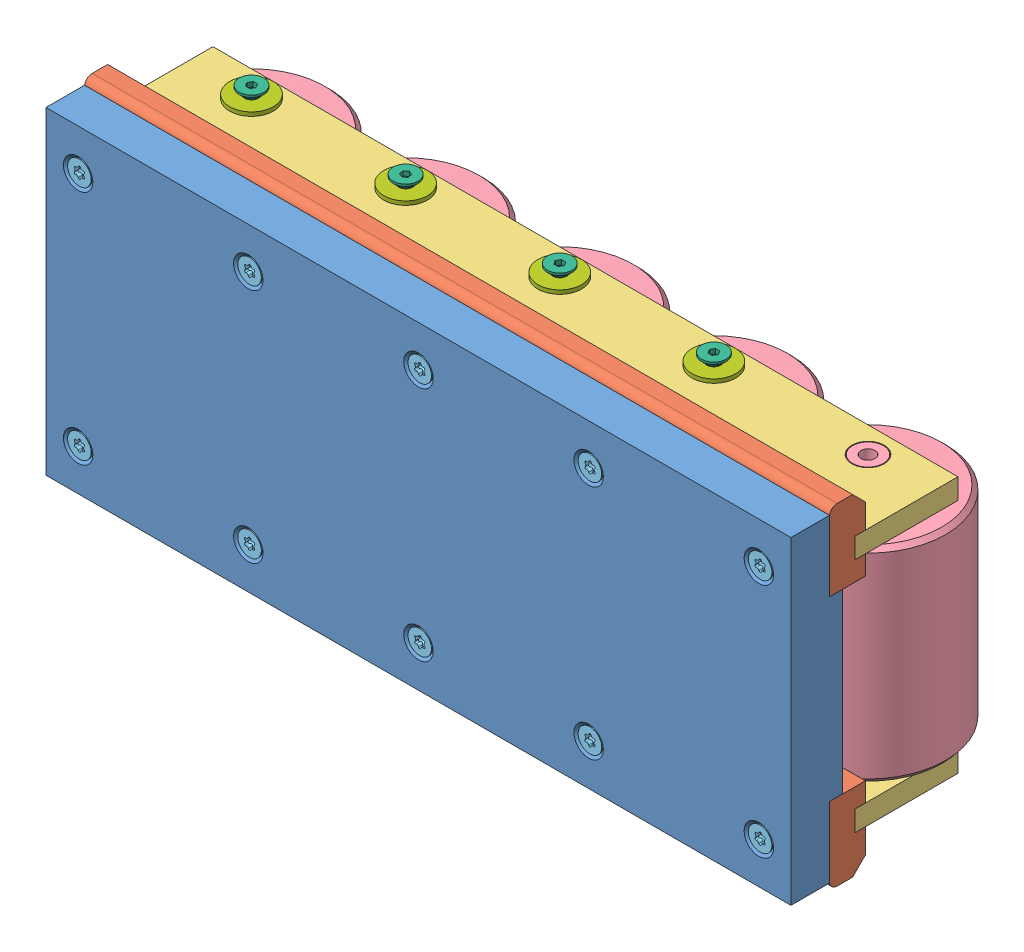
SolidWorks assembly Estrada Guerra Jorge Luis P60, configuration Predeterminado. Lengths in mm.
Overall size (604.52 258 194.9).
30 component instances, 7 part files, 54 mates.
Components (placement in the parent):
- P60.3-1: P60.3 [Predeterminado] at origin size (580 248 40)
- P60.2-1: P60.2 [Predeterminado] at (0 193 -58) x (1 0 0) z (0 -1 0) size (580 28 60)
- P60.2-2: P60.2 [Predeterminado] at (580 55 -58) x (-1 0 0) z (0 1 0) size (580 28 60)
- P60.1-2: P60.1 [Predeterminado] at (580 208 -130) x (0 1 0) z (1 0 0) size (16 80 580)
- P60.1-3: P60.1 [Predeterminado] at (0 40 -130) x (0 -1 0) z (-1 0 0) size (16 80 580)
- P60.4-1: P60.4 [Predeterminado] at (170 24 -110) x (-0.793535 0 0.608525) z (0 -1 0) size (121.11 121.11 200)
- P60.4-2: P60.4 [Predeterminado] at (290 24 -110) x (0.978566 0 -0.205935) z (0 -1 0) size (121.11 121.11 200)
- P60.4-3: P60.4 [Predeterminado] at (530 24 -110) x (1 0 0) z (0 -1 0) size (121.11 121.11 200)
- P60.4-4: P60.4 [Predeterminado] at (410 24 -110) x (1 0 0) z (0 -1 0) size (121.11 121.11 200)
- P60.4-5: P60.4 [Predeterminado] at (50 24 -110) x (0.998323 0 0.057885) z (0 -1 0) size (121.11 121.11 200)
- hexa csunk flathd screw_iso-1: hexa csunk flathd screw_iso [ISO 14581 M10x20x20-N] at (555 32 -1) size (18.3 18.3 20)
- hexa csunk flathd screw_iso-2: hexa csunk flathd screw_iso [ISO 14581 M10x20x20-N] at (555 216 -1) size (18.3 18.3 20)
- hexa csunk flathd screw_iso-3: hexa csunk flathd screw_iso [ISO 14581 M10x20x20-N] at (422.5 216 -1) size (18.3 18.3 20)
- hexa csunk flathd screw_iso-4: hexa csunk flathd screw_iso [ISO 14581 M10x20x20-N] at (157.5 32 -1) size (18.3 18.3 20)
- hexa csunk flathd screw_iso-5: hexa csunk flathd screw_iso [ISO 14581 M10x20x20-N] at (422.5 32 -1) size (18.3 18.3 20)
- hexa csunk flathd screw_iso-6: hexa csunk flathd screw_iso [ISO 14581 M10x20x20-N] at (290 32 -1) size (18.3 18.3 20)
- hexa csunk flathd screw_iso-7: hexa csunk flathd screw_iso [ISO 14581 M10x20x20-N] at (290 216 -1) size (18.3 18.3 20)
- hexa csunk flathd screw_iso-8: hexa csunk flathd screw_iso [ISO 14581 M10x20x20-N] at (157.5 216 -1) size (18.3 18.3 20)
- hexa csunk flathd screw_iso-9: hexa csunk flathd screw_iso [ISO 14581 M10x20x20-N] at (25 216 -1) size (18.3 18.3 20)
- hexa csunk flathd screw_iso-10: hexa csunk flathd screw_iso [ISO 14581 M10x20x20-N] at (25 32 -1) size (18.3 18.3 20)
- socket countersunk head screw_iso-1: socket countersunk head screw_iso [ISO 10642 - M10 x 50 - 50N] at (410 233.0828 -110) x (0 -1 0) z (0 0 1) size (50 19.22 19.22)
- plain washer xlarge grade c_iso-1: plain washer xlarge grade c_iso [Washer ISO 7094 - 10] at (410 224 -110) x (0 -1 0) z (0.546944 0 -0.837169) size (3 34 34)
- plain washer xlarge grade c_iso-2: plain washer xlarge grade c_iso [Washer ISO 7094 - 10] at (50 224 -110) x (0 -1 0) z (0.546944 0 -0.837169) size (3 34 34)
- socket countersunk head screw_iso-2: socket countersunk head screw_iso [ISO 10642 - M10 x 50 - 50N] at (50 233.0828 -110) x (0 -1 0) z (0 0 1) size (50 19.22 19.22)
- plain washer xlarge grade c_iso-3: plain washer xlarge grade c_iso [Washer ISO 7094 - 10] at (530 24 -110) x (0 1 0) z (0.546944 0 -0.837169) size (3 34 34)
- socket countersunk head screw_iso-3: socket countersunk head screw_iso [ISO 10642 - M10 x 50 - 50N] at (530 14.9172 -110) x (0 1 0) z (0 0 1) size (50 19.22 19.22)
- plain washer xlarge grade c_iso-4: plain washer xlarge grade c_iso [Washer ISO 7094 - 10] at (290 224 -110) x (0 -1 0) z (0.546944 0 -0.837169) size (3 34 34)
- socket countersunk head screw_iso-4: socket countersunk head screw_iso [ISO 10642 - M10 x 50 - 50N] at (290 233.0828 -110) x (0 -1 0) z (0 0 1) size (50 19.22 19.22)
- plain washer xlarge grade c_iso-5: plain washer xlarge grade c_iso [Washer ISO 7094 - 10] at (170 224 -110) x (0 -1 0) z (0.546944 0 -0.837169) size (3 34 34)
- socket countersunk head screw_iso-5: socket countersunk head screw_iso [ISO 10642 - M10 x 50 - 50N] at (170 233.0828 -110) x (0 -1 0) z (-0.346647 0 0.937996) size (50 19.22 19.22)
Mates (geometry in assembly coordinates):
- Coincidente1: coordinate: point of P60.3-1
- Coincidente2: coincident anti-aligned: plane of P60.3-1 through (580 248 -30) normal (0 0 -1); plane of P60.2-1 through (580 247 -30) normal (0 0 1)
- Coincidente3: coincident anti-aligned: plane of P60.3-1 through (580 193 -30) normal (0 1 0); plane of P60.2-1 through (580 193 -30) normal (0 -1 0)
- Coincidente4: coincident: line of P60.3-1 through (0 193 -30) axis (0 1 0); plane of P60.2-1 through (0 247 -36) normal (-1 0 0)
- Coincidente7: coincident anti-aligned: plane of P60.3-1 through (580 0 -30) normal (0 0 -1); plane of P60.2-2 through (0 1 -30) normal (0 0 1)
- Coincidente8: coincident anti-aligned: plane of P60.3-1 through (580 55 -30) normal (0 -1 0); plane of P60.2-2 through (0 55 -30) normal (0 1 0)
- Coincidente9: coincident aligned: line of P60.3-1 through (0 0 -30) axis (0 1 0); line of P60.2-2 through (0 1 -30) axis (0 1 0)
- Coincidente14: coincident anti-aligned: plane of P60.2-1 through (580 208 -50) normal (0 0 -1); plane of P60.1-2 through (580 224 -50) normal (0 0 1)
- Coincidente15: coincident anti-aligned: line of P60.2-1 through (580 208 -50) axis (-1 0 0); line of P60.1-2 through (0 208 -50) axis (1 0 0)
- Coincidente16: coincident anti-aligned: line of P60.2-1 through (0 208 -50) axis (0 1 0); line of P60.1-2 through (0 224 -50) axis (0 -1 0)
- Coincidente17: coincident anti-aligned: plane of P60.2-2 through (0 40 -50) normal (0 0 -1); plane of P60.1-3 through (0 24 -50) normal (0 0 1)
- Coincidente20: coincident anti-aligned: line of P60.2-2 through (0 40 -50) axis (1 0 0); line of P60.1-3 through (580 40 -50) axis (-1 0 0)
- Coincidente21: coincident anti-aligned: line of P60.2-2 through (0 40 -50) axis (0 -1 0); line of P60.1-3 through (0 24 -50) axis (0 1 0)
- Concéntrica3: concentric anti-aligned: cylinder of P60.1-2 through (50 224 -110) axis (0 -1 0) radius 12.6; cylinder of P60.4-5 through (50 224 -110) axis (0 1 0) radius 12.5
- Coincidente22: coincident aligned: circle of P60.1-2; plane of P60.4-5 through (49.2764 224 -97.521) normal (0 1 0)
- Concéntrica4: concentric anti-aligned: cylinder of P60.1-2 through (170 224 -110) axis (0 -1 0) radius 12.6; cylinder of P60.4-1 through (170 224 -110) axis (0 1 0) radius 12.5
- Concéntrica7: concentric aligned: circle of P60.1-3; circle of P60.4-1
- Coincidente23: coincident aligned: circle of P60.1-3; plane of P60.4-1 through (170 24 -110) normal (0 -1 0)
- Concéntrica8: concentric anti-aligned: cylinder of P60.1-2 through (290 224 -110) axis (0 -1 0) radius 12.6; cylinder of P60.4-2 through (290 224 -110) axis (0 1 0) radius 12.5
- Coincidente24: coincident aligned: circle of P60.1-2; plane of P60.4-2 through (292.5742 224 -97.7679) normal (0 1 0)
- Concéntrica9: concentric anti-aligned: cylinder of P60.1-2 through (410 224 -110) axis (0 -1 0) radius 12.6; cylinder of P60.4-4 through (410 224 -110) axis (0 1 0) radius 12.5
- Coincidente25: coincident aligned: circle of P60.1-2; plane of P60.4-4 through (410 224 -97.5) normal (0 1 0)
- Concéntrica10: concentric anti-aligned: cylinder of P60.1-2 through (530 224 -110) axis (0 -1 0) radius 12.6; cylinder of P60.4-3 through (530 224 -110) axis (0 1 0) radius 12.5
- Coincidente26: coincident aligned: circle of P60.1-2; plane of P60.4-3 through (530 224 -97.5) normal (0 1 0)
- Concéntrica21: concentric anti-aligned: cylinder of P60.3-1 through (555 32 -580) axis (0 0 1) radius 5.5; cylinder of hexa csunk flathd screw_iso-1 through (555 32 -1) axis (0 0 -1) radius 5
- Concéntrica22: concentric anti-aligned: cylinder of P60.3-1 through (555 216 -580) axis (0 0 1) radius 5.5; cylinder of hexa csunk flathd screw_iso-2 through (555 216 -1) axis (0 0 -1) radius 5
- Concéntrica23: concentric anti-aligned: circle of P60.3-1; cylinder of hexa csunk flathd screw_iso-3 through (422.5 216 -1) axis (0 0 -1) radius 5
- Concéntrica24: concentric anti-aligned: circle of P60.3-1; cylinder of hexa csunk flathd screw_iso-5 through (422.5 32 -1) axis (0 0 -1) radius 5
- Concéntrica25: concentric anti-aligned: circle of P60.3-1; cylinder of hexa csunk flathd screw_iso-7 through (290 216 -1) axis (0 0 -1) radius 5
- Concéntrica26: concentric anti-aligned: circle of P60.3-1; cylinder of hexa csunk flathd screw_iso-6 through (290 32 -1) axis (0 0 -1) radius 5
- Concéntrica27: concentric anti-aligned: circle of P60.3-1; cylinder of hexa csunk flathd screw_iso-8 through (157.5 216 -1) axis (0 0 -1) radius 5
- Concéntrica28: concentric anti-aligned: circle of P60.3-1; cylinder of hexa csunk flathd screw_iso-4 through (157.5 32 -1) axis (0 0 -1) radius 5
- Concéntrica29: concentric anti-aligned: circle of P60.3-1; cylinder of hexa csunk flathd screw_iso-9 through (25 216 -1) axis (0 0 -1) radius 5
- Concéntrica30: concentric anti-aligned: circle of P60.3-1; cylinder of hexa csunk flathd screw_iso-10 through (25 32 -1) axis (0 0 -1) radius 5
- Concéntrica31: concentric anti-aligned: circle of socket countersunk head screw_iso-1; circle of plain washer xlarge grade c_iso-1
- Coincidente27: coincident aligned: circle of socket countersunk head screw_iso-1; plane of plain washer xlarge grade c_iso-1 through (395.7681 227 -119.2981) normal (0 1 0)
- Concéntrica32: concentric anti-aligned: unknown of plain washer xlarge grade c_iso-2; unknown of socket countersunk head screw_iso-2
- Coincidente28: coincident aligned: plane of plain washer xlarge grade c_iso-2 through (35.7681 227 -119.2981) normal (0 1 0); unknown of socket countersunk head screw_iso-2
- Concéntrica33: concentric anti-aligned: unknown of plain washer xlarge grade c_iso-3; unknown of socket countersunk head screw_iso-3
- Coincidente29: coincident aligned: plane of plain washer xlarge grade c_iso-3 through (544.2319 21 -100.7019) normal (0 -1 0); unknown of socket countersunk head screw_iso-3
- Concéntrica34: concentric anti-aligned: unknown of plain washer xlarge grade c_iso-4; unknown of socket countersunk head screw_iso-4
- Coincidente30: coincident aligned: plane of plain washer xlarge grade c_iso-4 through (275.7681 227 -119.2981) normal (0 1 0); unknown of socket countersunk head screw_iso-4
- Concéntrica35: concentric anti-aligned: unknown of plain washer xlarge grade c_iso-5; unknown of socket countersunk head screw_iso-5
- Coincidente31: coincident aligned: plane of plain washer xlarge grade c_iso-5 through (155.7681 227 -119.2981) normal (0 1 0); unknown of socket countersunk head screw_iso-5
- Coincidente37: coincident aligned: circle of P60.4-4; cylinder of socket countersunk head screw_iso-1 through (410 233.0828 -110) axis (0 1 0) radius 5
- Coincidente38: coincident anti-aligned: plane of P60.4-4 through (410 224 -97.5) normal (0 1 0); plane of plain washer xlarge grade c_iso-1 through (405.3956 224 -113.0082) normal (0 -1 0)
- Concéntrica42: concentric aligned: cylinder of P60.4-2 through (290 224 -110) axis (0 1 0) radius 5.5; cylinder of socket countersunk head screw_iso-4 through (290 233.0828 -110) axis (0 1 0) radius 5
- Coincidente40: coincident anti-aligned: plane of P60.4-2 through (292.5742 224 -97.7679) normal (0 1 0); plane of plain washer xlarge grade c_iso-4 through (285.3956 224 -113.0082) normal (0 -1 0)
- Concéntrica43: concentric aligned: cylinder of P60.4-1 through (170 224 -110) axis (0 1 0) radius 5.5; circle of plain washer xlarge grade c_iso-5
- Coincidente42: coincident anti-aligned: plane of P60.4-1 through (162.3934 224 -119.9192) normal (0 1 0); plane of plain washer xlarge grade c_iso-5 through (165.3956 224 -113.0082) normal (0 -1 0)
- Concéntrica45: concentric aligned: cylinder of P60.4-5 through (50 224 -110) axis (0 1 0) radius 5.5; cylinder of socket countersunk head screw_iso-2 through (50 233.0828 -110) axis (0 1 0) radius 5
- Coincidente43: coincident anti-aligned: plane of P60.4-5 through (49.2764 224 -97.521) normal (0 1 0); plane of plain washer xlarge grade c_iso-2 through (45.3956 224 -113.0082) normal (0 -1 0)
- Concéntrica46: concentric aligned: cylinder of P60.4-3 through (530 24 -110) axis (0 -1 0) radius 5.5; cylinder of socket countersunk head screw_iso-3 through (530 14.9172 -110) axis (0 -1 0) radius 5
- Coincidente44: coincident anti-aligned: plane of P60.4-3 through (530 24 -110) normal (0 -1 0); plane of plain washer xlarge grade c_iso-3 through (534.6044 24 -106.9918) normal (0 1 0)
